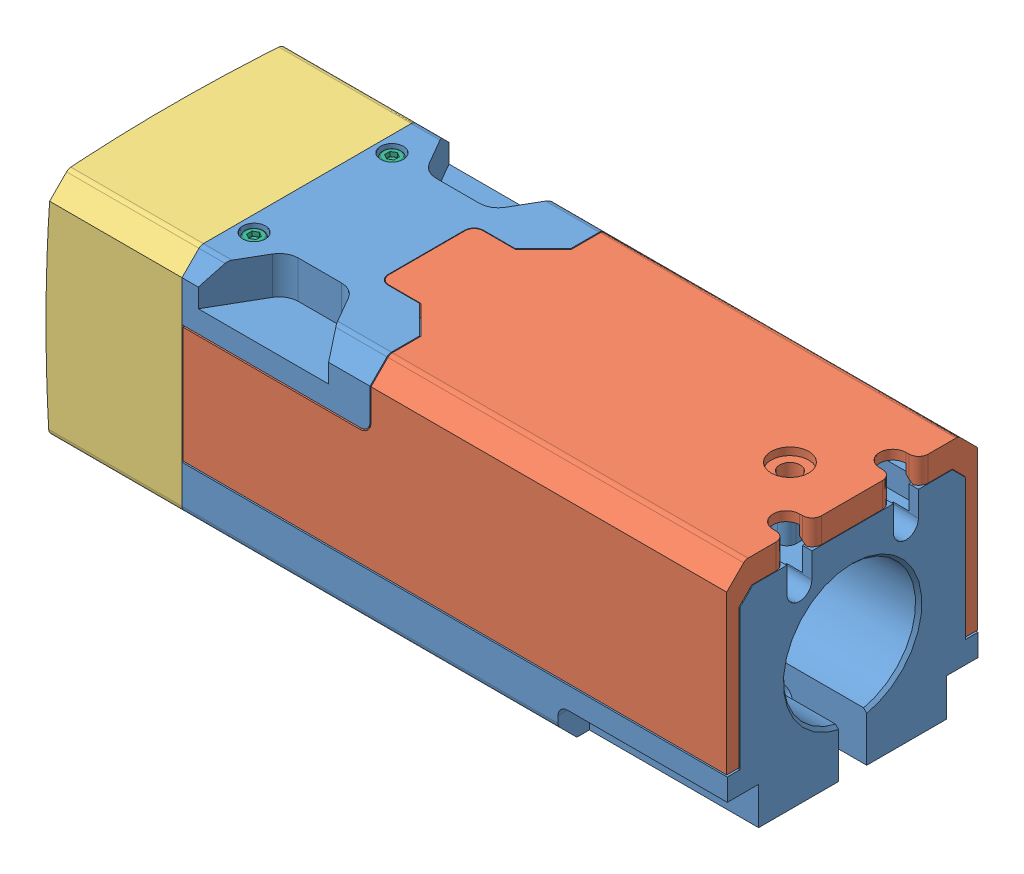
SolidWorks assembly 17mm测速, configuration 默认. Lengths in mm.
Overall size (110.7 38.1 40.64).
18 component instances, 6 part files, 0 mates.
Components (placement in the parent):
- RM2016 17mm子弹 测速机构 基座-1: RM2016 17mm子弹 测速机构 基座 [默认] at origin size (87 38 40)
- RM2016 17mm子弹 测速机构 顶盖-1: RM2016 17mm子弹 测速机构 顶盖 [默认] at (-0.0927 28.25 0) x (1 0 0) z (0 1 0) size (87.95 40 28.25)
- RM2016 17mm子弹 测速机构 枪头罩-1: RM2016 17mm子弹 测速机构 枪头罩 [默认] at (-104.5 16 0) size (28.7 38 40.64)
- 绿激光罩WiFi通信版-1: 绿激光罩WiFi通信版 [默认] at (-92.3 25.1772 -13.1064) x (0 0.998445 -0.055749) z (0 0.055749 0.998445) size (8 8.8 8)
- 铜镶件WiFi通信版-1: 铜镶件WiFi通信版 [默认] at (-7.5 1 9) x (0 0 1) z (-1 0 0) size (6 4 4)
- 铜镶件WiFi通信版-2: 铜镶件WiFi通信版 [默认] at (-20 -2 8.625) x (0 1 0) z (-1 0 0) size (6 4 4)
- 铜镶件WiFi通信版-3: 铜镶件WiFi通信版 [默认] at (-20 -2 -8.625) x (0 1 0) z (-1 0 0) size (6 4 4)
- 铜镶件WiFi通信版-4: 铜镶件WiFi通信版 [默认] at (-60 -2 8.625) x (0 1 0) z (-1 0 0) size (6 4 4)
- 铜镶件WiFi通信版-5: 铜镶件WiFi通信版 [默认] at (-60 -2 -8.625) x (0 1 0) z (-1 0 0) size (6 4 4)
- hexagon socket head cap screws gb_GB_FASTENER_SCREWS_HSHCS M1.6X3-C-1: hexagon socket head cap screws gb_GB_FASTENER_SCREWS_HSHCS M1.6X3-C [默认] at (-78.5 35.6 11) x (0 -1 0) z (0 0 1) size (4.6 3 3)
- hexagon socket head cap screws gb_GB_FASTENER_SCREWS_HSHCS M1.6X3-C-2: hexagon socket head cap screws gb_GB_FASTENER_SCREWS_HSHCS M1.6X3-C [默认] at (-78.5 35.6 -11) x (0 -1 0) z (0 0 1) size (4.6 3 3)
- hexagon socket head cap screws gb_GB_FASTENER_SCREWS_HSHCS M1.6X3-C-3: hexagon socket head cap screws gb_GB_FASTENER_SCREWS_HSHCS M1.6X3-C [默认] at (-78.5 -1.1 -7) x (0 1 0) z (0 0 1) size (4.6 3 3)
- hexagon socket head cap screws gb_GB_FASTENER_SCREWS_HSHCS M1.6X3-C-4: hexagon socket head cap screws gb_GB_FASTENER_SCREWS_HSHCS M1.6X3-C [默认] at (-78.5 -2.1 7) x (0 1 0) z (0 0 1) size (4.6 3 3)
- hexagon socket head cap screws gb_GB_FASTENER_SCREWS_HSHCS M1.6X3-C-5: hexagon socket head cap screws gb_GB_FASTENER_SCREWS_HSHCS M1.6X3-C [默认] at (-23 17 16.65) x (0 0 -1) z (1 0 0) size (4.6 3 3)
- hexagon socket head cap screws gb_GB_FASTENER_SCREWS_HSHCS M1.6X3-C-6: hexagon socket head cap screws gb_GB_FASTENER_SCREWS_HSHCS M1.6X3-C [默认] at (-14.1 33.55 14) x (0 -1 0) z (0 0 1) size (4.6 3 3)
- hexagon socket head cap screws gb_GB_FASTENER_SCREWS_HSHCS M1.6X3-C-7: hexagon socket head cap screws gb_GB_FASTENER_SCREWS_HSHCS M1.6X3-C [默认] at (-48.1 33.55 14) x (0 -1 0) z (0 0 1) size (4.6 3 3)
- hexagon socket head cap screws gb_GB_FASTENER_SCREWS_HSHCS M1.6X3-C-8: hexagon socket head cap screws gb_GB_FASTENER_SCREWS_HSHCS M1.6X3-C [默认] at (-48.1 33.55 -14) x (0 -1 0) z (0.678493 0 -0.734607) size (4.6 3 3)
- hexagon socket head cap screws gb_GB_FASTENER_SCREWS_HSHCS M1.6X3-C-9: hexagon socket head cap screws gb_GB_FASTENER_SCREWS_HSHCS M1.6X3-C [默认] at (-14.1 33.55 -14) x (0 -1 0) z (0 0 1) size (4.6 3 3)
